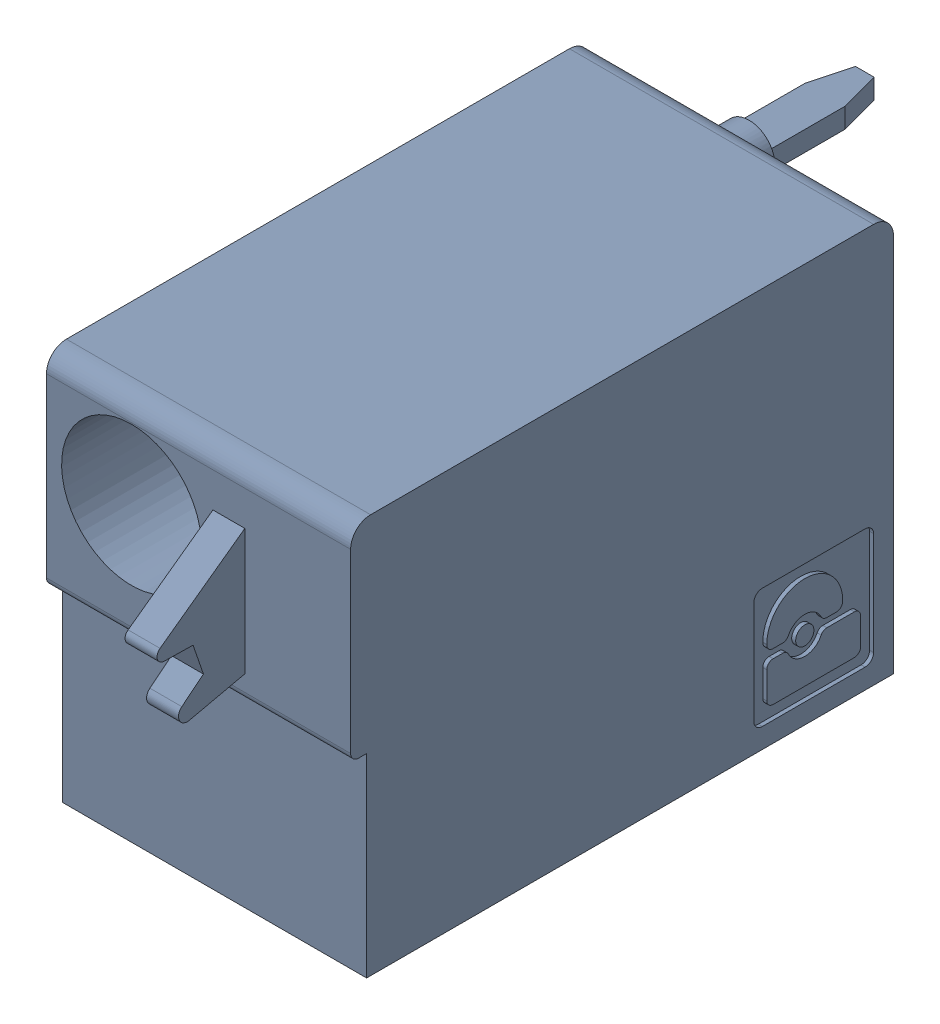
SolidWorks assembly J88, configuration Default. Lengths in mm.
Overall size (7.62 10 19.2).
2 component instances, 1 part files, 0 mates.
Components (placement in the parent):
- 1790487-1: 1790487 [Default] at (239.165 -15.67 -10.6) x (0 1 0) z (1 0 0) size (10 19.2 7.62)
  - ffkdsa1-v2-7.62-1: ffkdsa1-v2-7.62 [Default] at (-15.6914 -27.508 9.12) x (0 -1 0) z (0 0 1) size (19.2 10 7.62)
